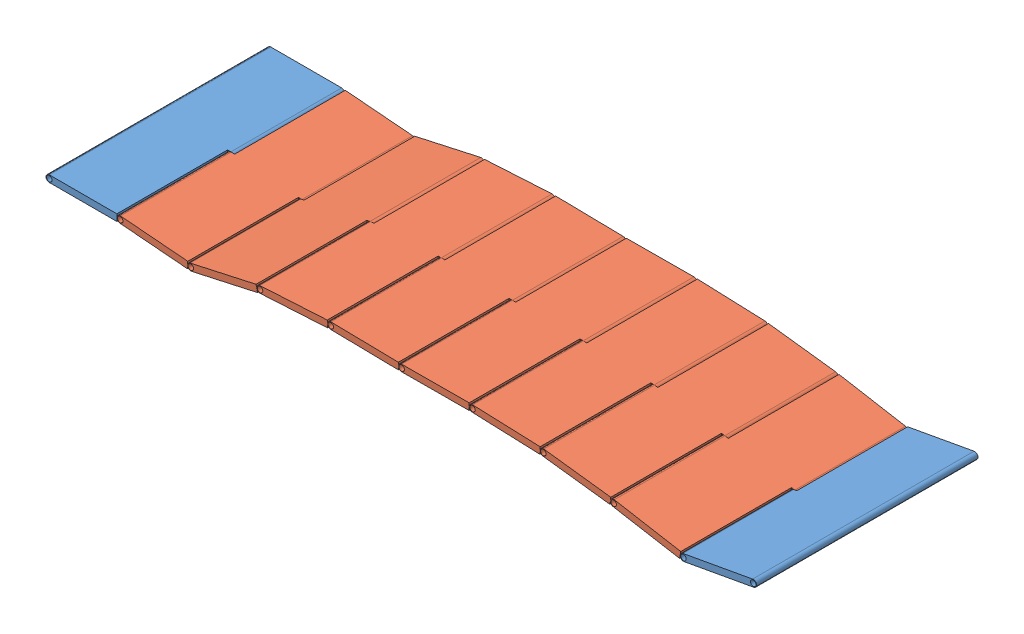
SolidWorks assembly Foothpath Assembly, configuration Default. Lengths in mm.
Overall size (3210.72 143.56 1000).
10 component instances, 2 part files, 18 mates.
Components (placement in the parent):
- Part3-1: Part3 [Default] at (461.7621 530.9087 704.5493) x (0 0 -1) z (1 0 0) size (1000 30 350)
- part2-1: part2 [Default] at (782.4556 547.5209 704.5493) x (0 0 -1) z (-0.083347 -0.996521 0) size (1000 350 30)
- part2-2: part2 [Default] at (1093.6481 568.392 704.5493) x (0 0 -1) z (0.215672 -0.976466 0) size (1000 350 30)
- part2-3: part2 [Default] at (3010.1252 538.3887 704.5493) x (0 0 -1) z (-0.171557 -0.985174 0) size (1000 350 30)
- part2-5: part2 [Default] at (2692.9518 585.4801 704.5493) x (0 0 -1) z (-0.122075 -0.992521 0) size (1000 350 30)
- part2-6: part2 [Default] at (1412.0048 612.3332 704.5493) x (0 0 -1) z (0.056906 -0.99838 0) size (1000 350 30)
- part2-7: part2 [Default] at (1732.8359 618.6773 704.5493) x (0 0 -1) z (-0.017393 -0.999849 0) size (1000 350 30)
- part2-8: part2 [Default] at (2052.485 616.5822 704.5493) x (0 0 -1) z (0.004285 -0.999991 0) size (1000 350 30)
- part2-9: part2 [Default] at (2373.0018 611.1852 704.5493) x (0 0 -1) z (-0.037949 -0.99928 0) size (1000 350 30)
- Part3-3: Part3 [Default] at (3325.2897 509.9387 704.5493) x (0 0 1) z (-0.983967 -0.178352 0) size (1000 30 350)
Mates (geometry in assembly coordinates):
- Concentric1: concentric anti-aligned: cylinder of Part3-1 through (621.7621 545.9087 704.5493) axis (0 0 -1) radius 12.5; cylinder of part2-1 through (621.7621 545.9087 704.5493) axis (0 0 1) radius 12.5
- Coincident1: coincident aligned: plane of Part3-1 through (316.7621 560.9087 1204.5493) normal (0 0 1); plane of part2-1 through (924.4506 505.5399 1204.5493) normal (0 0 1)
- Concentric2: concentric anti-aligned: cylinder of part2-1 through (940.6486 519.2375 704.5493) axis (0 0 -1) radius 12.5; cylinder of part2-2 through (940.6486 519.2375 704.5493) axis (0 0 1) radius 12.5
- Coincident2: coincident aligned: plane of part2-1 through (924.4506 505.5399 1204.5493) normal (0 0 1); plane of part2-2 through (1241.7058 570.3705 1204.5493) normal (0 0 1)
- Concentric3: concentric anti-aligned: cylinder of part2-2 through (1253.1177 588.2525 704.5493) axis (0 0 -1) radius 12.5; cylinder of part2-6 through (1253.1177 588.2525 704.5493) axis (0 0 1) radius 12.5
- Coincident3: coincident aligned: plane of part2-2 through (1241.7058 570.3705 1204.5493) normal (0 0 1); plane of part2-6 through (1558.4771 590.6331 1204.5493) normal (0 0 1)
- Concentric4: concentric anti-aligned: cylinder of part2-6 through (1572.5992 606.4624 704.5493) axis (0 0 -1) radius 12.5; cylinder of part2-7 through (1572.5992 606.4624 704.5493) axis (0 0 1) radius 12.5
- Coincident4: coincident aligned: plane of part2-6 through (1558.4771 590.6331 1204.5493) normal (0 0 1); plane of part2-7 through (1877.2921 586.1599 1204.5493) normal (0 0 1)
- Concentric5: concentric anti-aligned: cylinder of part2-7 through (1892.5508 600.8968 704.5493) axis (0 0 -1) radius 12.5; cylinder of part2-8 through (1892.5508 600.8968 704.5493) axis (0 0 1) radius 12.5
- Coincident5: coincident aligned: plane of part2-7 through (1877.2921 586.1599 1204.5493) normal (0 0 1); plane of part2-8 through (2197.6122 587.2037 1204.5493) normal (0 0 1)
- Concentric6: concentric anti-aligned: cylinder of part2-8 through (2212.5478 602.2678 704.5493) axis (0 0 -1) radius 12.5; cylinder of part2-9 through (2212.5478 602.2678 704.5493) axis (0 0 1) radius 12.5
- Coincident6: coincident aligned: plane of part2-8 through (2197.6122 587.2037 1204.5493) normal (0 0 1); plane of part2-9 through (2516.7589 575.7042 1204.5493) normal (0 0 1)
- Concentric7: concentric anti-aligned: cylinder of part2-5 through (2532.3173 590.1242 704.5493) axis (0 0 1) radius 12.5; cylinder of part2-9 through (2532.3173 590.1242 704.5493) axis (0 0 -1) radius 12.5
- Coincident7: coincident aligned: plane of part2-5 through (2833.2051 538.0036 1204.5493) normal (0 0 1); plane of part2-9 through (2516.7589 575.7042 1204.5493) normal (0 0 1)
- Concentric8: concentric anti-aligned: cylinder of part2-3 through (2849.924 551.0603 704.5493) axis (0 0 1) radius 12.5; cylinder of part2-5 through (2849.924 551.0603 704.5493) axis (0 0 -1) radius 12.5
- Coincident8: coincident aligned: plane of part2-3 through (3147.8288 483.9577 1204.5493) normal (0 0 1); plane of part2-5 through (2833.2051 538.0036 1204.5493) normal (0 0 1)
- Concentric10: concentric anti-aligned: cylinder of part2-3 through (3165.1797 496.1619 704.5493) axis (0 0 -1) radius 12.5; cylinder of Part3-3 through (3165.1797 496.1619 704.5493) axis (0 0 1) radius 12.5
- Coincident10: coincident aligned: plane of part2-3 through (3147.8288 483.9577 1204.5493) normal (0 0 1); plane of Part3-3 through (3462.6143 565.3188 1204.5493) normal (0 0 1)
